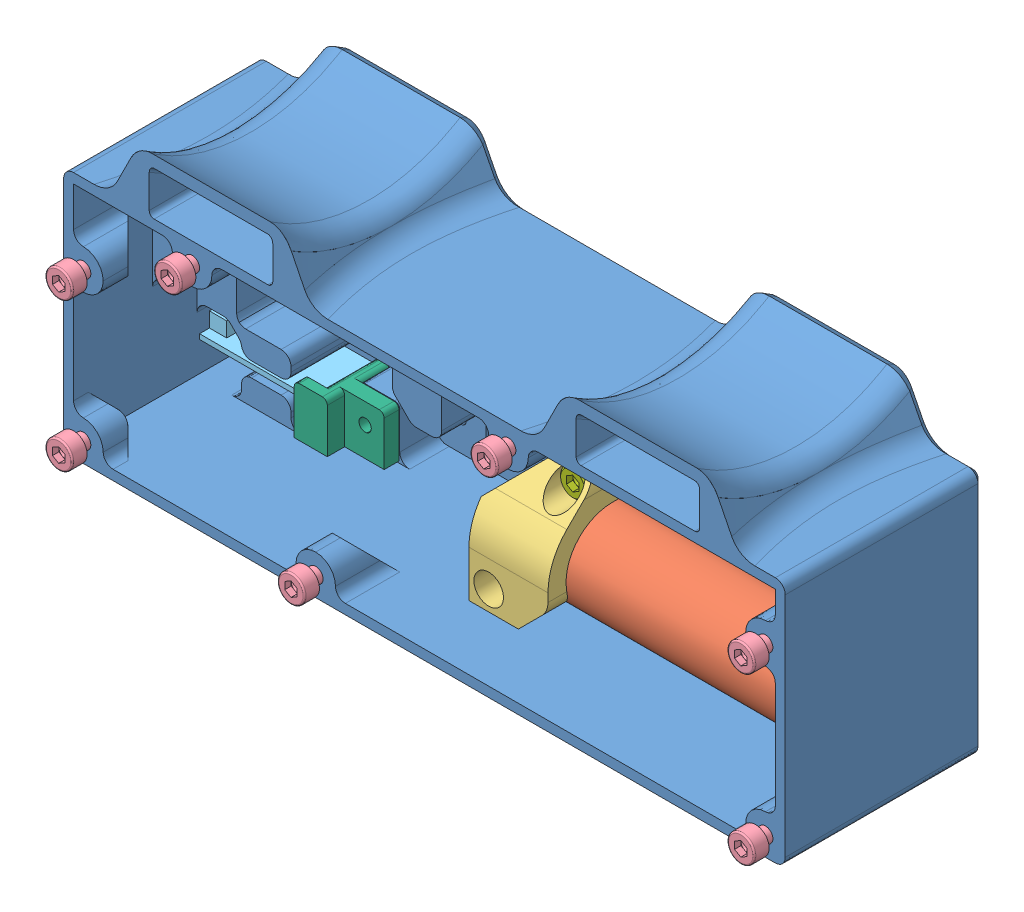
SolidWorks assembly TO-999, configuration Standard. Lengths in mm.
Overall size (146 61.68 45.85).
22 component instances, 8 part files, 75 mates.
Components (placement in the parent):
- TO-001-1: TO-001 [Standard] at origin size (146 61.68 40.85)
- socket head cap screw_am-1: socket head cap screw_am [B18.3.1M - 1.6 x 0.35 x 3 Hex SHCS -- 3NHX] at (97.7855 41.9451 16.2) x (0 0 -1) z (1 0 0) size (4.6 3 3) (hidden)
- socket head cap screw_am-2: socket head cap screw_am [B18.3.1M - 1.6 x 0.35 x 3 Hex SHCS -- 3NHX] at (138.85 24.8 16.2) x (0 0 -1) z (1 0 0) size (4.6 3 3) (hidden)
- socket head cap screw_am-4: socket head cap screw_am [B18.3.1M - 2.5 x 0.45 x 20 Hex SHCS -- 20NHX] at (48.5 42 28) x (0 0 -1) z (1 0 0) size (22.5 4.5 4.5) (hidden)
- socket head cap screw_am-5: socket head cap screw_am [B18.3.1M - 2.5 x 0.45 x 20 Hex SHCS -- 20NHX] at (48.5 17.5 28) x (0 0 -1) z (1 0 0) size (22.5 4.5 4.5) (hidden)
- socket head cap screw_am-6: socket head cap screw_am [B18.3.1M - 2.5 x 0.45 x 20 Hex SHCS -- 20NHX] at (2 17.5 28) x (0 0 -1) z (1 0 0) size (22.5 4.5 4.5) (hidden)
- socket head cap screw_am-7: socket head cap screw_am [B18.3.1M - 2.5 x 0.45 x 20 Hex SHCS -- 20NHX] at (2 42 28) x (0 0 -1) z (1 0 0) size (22.5 4.5 4.5) (hidden)
- Battery-1: Battery [Standard] at (75 9.35 15) x (0 0 -1) z (1 0 0) size (18 18 65)
- To-002-1: To-002 [Standard] at origin size (142 46 28)
- socket head cap screw 4762_din-1: socket head cap screw 4762_din [EN ISO 4762 M1.6 x 2.5 - 2.5N] at (97.7855 41.9451 16.2) x (0 0 -1) z (1 0 0) size (4.1 3 3)
- TO-003-1: TO-003 [Standard] at origin size (146 50 2) (hidden)
- socket head cap screw 4762_din-20: socket head cap screw 4762_din [EN ISO 4762 M3 x 8 - 8N] at (23 43 45) x (0 0 -1) z (1 0 0) size (11 5.5 5.5)
- socket head cap screw 4762_din-21: socket head cap screw 4762_din [EN ISO 4762 M3 x 8 - 8N] at (87 43 45) x (0 0 -1) z (1 0 0) size (11 5.5 5.5)
- socket head cap screw 4762_din-22: socket head cap screw 4762_din [EN ISO 4762 M3 x 8 - 8N] at (139 34.5 45) x (0 0 -1) z (1 0 0) size (11 5.5 5.5)
- socket head cap screw 4762_din-24: socket head cap screw 4762_din [EN ISO 4762 M3 x 8 - 8N] at (48 1 45) x (0 0 -1) z (1 0 0) size (11 5.5 5.5)
- socket head cap screw 4762_din-25: socket head cap screw 4762_din [EN ISO 4762 M3 x 8 - 8N] at (1 1 45) x (0 0 -1) z (1 0 0) size (11 5.5 5.5)
- socket head cap screw 4762_din-26: socket head cap screw 4762_din [EN ISO 4762 M3 x 8 - 8N] at (1 31 45) x (0 0 -1) z (1 0 0) size (11 5.5 5.5)
- socket head cap screw 4762_din-27: socket head cap screw 4762_din [EN ISO 4762 M3 x 8 - 8N] at (139 1 45) x (0 0 -1) z (1 0 0) size (11 5.5 5.5)
- TP5000_placeholder-1: TP5000_placeholder [Standard] at (-1 5 14.5) x (1 0 0) z (0 1 0) size (27 12.5 4)
- TO-004-1: TO-004 [Standard] at (26.85 -0.6295 10) x (1 0 0) z (0 1 0) size (14.7 12.5 10)
- socket head cap screw_am-8: socket head cap screw_am [B18.3.1M - 3 x 0.5 x 5 Hex SHCS -- 5NHX] at (79 22 19) x (0 0 -1) z (1 0 0) size (8 5.5 5.5)
- socket head cap screw_am-9: socket head cap screw_am [B18.3.1M - 3 x 0.5 x 5 Hex SHCS -- 5NHX] at (71 4 19) x (0 0 -1) z (1 0 0) size (8 5.5 5.5)
Mates (geometry in assembly coordinates):
- Konzentrisch1: concentric: cylinder of TO-001-1 through (138.85 24.8 13) axis (0 0 1) radius 0.9; cylinder of ? through (138.85 24.8 13) axis (0 0 1) radius 1
- Parallel1: parallel: plane of TO-001-1 through (141 45 40) normal (-1 0 0); plane of ? through (140.6177 22.9225 13) normal (1 0 0)
- Deckungsgleich2: coincident: plane of TO-001-1 through (130.3 33.55 13) normal (0 0 1); plane of ? through (140.6177 43.8225 13) normal (0 0 -1)
- Konzentrisch2: concentric: cylinder of TO-001-1 through (1 41.5 15) axis (0 0 1) radius 0.9; cylinder of ? through (2 42 25.5) axis (0 0 -1) radius 1.5
- Konzentrisch3: concentric: cylinder of TO-001-1 through (52.5 18 15) axis (0 0 1) radius 0.9; cylinder of ? through (48.5 17.5 25.5) axis (0 0 -1) radius 1.5
- Deckungsgleich4: coincident: plane of TO-001-1 through (0 0 24) normal (0 0 1); plane of ? through (25.25 29.75 24) normal (0 0 -1)
- Konzentrisch4: concentric: cylinder of ? through (97.7855 41.9451 13) axis (0 0 1) radius 1; cylinder of socket head cap screw_am-1 through (97.7855 41.9451 47.95) axis (0 0 1) radius 1.5
- Deckungsgleich5: coincident: plane of ? through (140.6177 43.8225 14.6) normal (0 0 1); plane of socket head cap screw_am-1 through (97.7855 43.4451 14.6) normal (0 0 -1)
- Konzentrisch5: concentric: cylinder of ? through (138.85 24.8 13) axis (0 0 1) radius 1; cylinder of socket head cap screw_am-2 through (138.85 24.8 47.95) axis (0 0 1) radius 1.5
- Deckungsgleich6: coincident: plane of ? through (140.6177 43.8225 14.6) normal (0 0 1); plane of socket head cap screw_am-2 through (138.85 26.3 14.6) normal (0 0 -1)
- Konzentrisch7: concentric: cylinder of ? through (48.5 42 25.5) axis (0 0 -1) radius 1.5; cylinder of socket head cap screw_am-4 through (48.5 42 59.75) axis (0 0 1) radius 2.25
- Deckungsgleich8: coincident: plane of ? through (25.25 29.75 25.5) normal (0 0 1); plane of socket head cap screw_am-4 through (48.5 44.25 25.5) normal (0 0 -1)
- Konzentrisch8: concentric: cylinder of ? through (48.5 17.5 25.5) axis (0 0 -1) radius 1.5; cylinder of socket head cap screw_am-5 through (48.5 17.5 59.75) axis (0 0 1) radius 2.25
- Deckungsgleich9: coincident: plane of ? through (25.25 29.75 25.5) normal (0 0 1); plane of socket head cap screw_am-5 through (48.5 19.75 25.5) normal (0 0 -1)
- Konzentrisch9: concentric: cylinder of ? through (2 17.5 25.5) axis (0 0 -1) radius 1.5; cylinder of socket head cap screw_am-6 through (2 17.5 59.75) axis (0 0 1) radius 2.25
- Deckungsgleich10: coincident: plane of ? through (25.25 29.75 25.5) normal (0 0 1); plane of socket head cap screw_am-6 through (2 19.75 25.5) normal (0 0 -1)
- Konzentrisch10: concentric: cylinder of ? through (2 42 25.5) axis (0 0 -1) radius 1.5; cylinder of socket head cap screw_am-7 through (2 42 59.75) axis (0 0 1) radius 2.25
- Deckungsgleich11: coincident: plane of ? through (25.25 29.75 25.5) normal (0 0 1); plane of socket head cap screw_am-7 through (2 44.25 25.5) normal (0 0 -1)
- Konzentrisch11: concentric: cylinder of TO-001-1 through (135 9.35 15) axis (1 0 0) radius 9.35; cylinder of Battery-1 through (140 9.35 15) axis (-1 0 0) radius 9
- Abstand1: distance = 1 mm: plane of Battery-1 through (140 9.35 15) normal (1 0 0); plane of TO-001-1 through (141 45 40) normal (-1 0 0)
- Konzentrisch12: concentric: cylinder of TO-001-1 through (79 22 8) axis (0 0 1) radius 1.25; cylinder of To-002-1 through (79 22 2) axis (0 0 -1) radius 1.5
- Konzentrisch13: concentric: cylinder of TO-001-1 through (71 4 8) axis (0 0 1) radius 1.25; cylinder of To-002-1 through (71 4 2) axis (0 0 -1) radius 1.5
- Konzentrisch14: concentric: cylinder of ? through (97.7855 41.9451 13) axis (0 0 1) radius 1; cylinder of socket head cap screw 4762_din-1 through (97.7855 41.9451 47.95) axis (0 0 1) radius 1.5
- Deckungsgleich13: coincident: plane of ? through (140.6177 43.8225 14.6) normal (0 0 1); plane of socket head cap screw 4762_din-1 through (97.7855 43.4451 14.6) normal (0 0 -1)
- Konzentrisch15: concentric: cylinder of ? through (138.85 24.8 13) axis (0 0 1) radius 1; cylinder of socket head cap screw_am-2 through (138.85 24.8 47.95) axis (0 0 1) radius 1.5
- Deckungsgleich14: coincident: plane of ? through (140.6177 43.8225 14.6) normal (0 0 1); plane of socket head cap screw_am-2 through (138.85 26.3 14.6) normal (0 0 -1)
- Konzentrisch16: concentric: cylinder of To-002-1 through (79 22 2) axis (0 0 -1) radius 1.5; cylinder of ? through (79 22 50.25) axis (0 0 1) radius 2.25
- Deckungsgleich15: coincident: plane of To-002-1 through (79 22 16) normal (0 0 1); plane of ? through (79 24.25 16) normal (0 0 -1)
- Konzentrisch17: concentric: cylinder of To-002-1 through (61 22 2) axis (0 0 -1) radius 1.5; cylinder of ? through (61 22 50.25) axis (0 0 1) radius 2.25
- Deckungsgleich16: coincident: plane of To-002-1 through (61 22 16) normal (0 0 1); plane of ? through (61 24.25 16) normal (0 0 -1)
- Konzentrisch18: concentric: cylinder of To-002-1 through (71 4 2) axis (0 0 -1) radius 1.5; cylinder of ? through (71 4 50.25) axis (0 0 1) radius 2.25
- Deckungsgleich17: coincident: plane of To-002-1 through (71 4 16) normal (0 0 1); plane of ? through (71 6.25 16) normal (0 0 -1)
- Konzentrisch19: concentric: cylinder of ? through (48.5 17.5 25.5) axis (0 0 -1) radius 1.5; cylinder of socket head cap screw_am-5 through (48.5 17.5 59.75) axis (0 0 1) radius 2.25
- Deckungsgleich18: coincident: plane of ? through (25.25 29.75 25.5) normal (0 0 1); plane of socket head cap screw_am-5 through (48.5 19.75 25.5) normal (0 0 -1)
- Konzentrisch20: concentric: cylinder of ? through (48.5 42 25.5) axis (0 0 -1) radius 1.5; cylinder of socket head cap screw_am-4 through (48.5 42 59.75) axis (0 0 1) radius 2.25
- Deckungsgleich19: coincident: plane of ? through (25.25 29.75 25.5) normal (0 0 1); plane of socket head cap screw_am-4 through (48.5 44.25 25.5) normal (0 0 -1)
- Konzentrisch21: concentric: cylinder of ? through (2 42 25.5) axis (0 0 -1) radius 1.5; cylinder of socket head cap screw_am-7 through (2 42 59.75) axis (0 0 1) radius 2.25
- Deckungsgleich20: coincident: plane of ? through (25.25 29.75 25.5) normal (0 0 1); plane of socket head cap screw_am-7 through (2 44.25 25.5) normal (0 0 -1)
- Konzentrisch22: concentric: cylinder of ? through (2 17.5 25.5) axis (0 0 -1) radius 1.5; cylinder of socket head cap screw_am-6 through (2 17.5 59.75) axis (0 0 1) radius 2.25
- Deckungsgleich21: coincident: plane of ? through (25.25 29.75 25.5) normal (0 0 1); plane of socket head cap screw_am-6 through (2 19.75 25.5) normal (0 0 -1)
- Konzentrisch23: concentric: cylinder of ? through (48.5 42 25.5) axis (0 0 -1) radius 1.5; cylinder of socket head cap screw_am-4 through (48.5 42 59.75) axis (0 0 1) radius 2.25
- Deckungsgleich22: coincident: plane of ? through (25.25 29.75 25.5) normal (0 0 1); plane of socket head cap screw_am-4 through (48.5 44.25 25.5) normal (0 0 -1)
- Konzentrisch24: concentric: cylinder of ? through (48.5 17.5 25.5) axis (0 0 -1) radius 1.5; cylinder of socket head cap screw_am-5 through (48.5 17.5 59.75) axis (0 0 1) radius 2.25
- Deckungsgleich23: coincident: plane of ? through (25.25 29.75 25.5) normal (0 0 1); plane of socket head cap screw_am-5 through (48.5 19.75 25.5) normal (0 0 -1)
- Konzentrisch25: concentric: cylinder of ? through (2 42 25.5) axis (0 0 -1) radius 1.5; cylinder of socket head cap screw_am-7 through (2 42 59.75) axis (0 0 1) radius 2.25
- Deckungsgleich24: coincident: plane of ? through (25.25 29.75 25.5) normal (0 0 1); plane of socket head cap screw_am-7 through (2 44.25 25.5) normal (0 0 -1)
- Konzentrisch26: concentric: cylinder of ? through (2 17.5 25.5) axis (0 0 -1) radius 1.5; cylinder of socket head cap screw_am-6 through (2 17.5 59.75) axis (0 0 1) radius 2.25
- Deckungsgleich25: coincident: plane of ? through (25.25 29.75 25.5) normal (0 0 1); plane of socket head cap screw_am-6 through (2 19.75 25.5) normal (0 0 -1)
- Deckungsgleich26: coincident: plane of TO-001-1 through (-158 63.1337 40) normal (0 0 1); plane of TO-003-1 through (0 0 40) normal (0 0 -1)
- Konzentrisch27: concentric: cylinder of TO-001-1 through (23 43 40) axis (0 0 1) radius 1.25; cylinder of TO-003-1 through (23 43 42) axis (0 0 1) radius 1.25
- Konzentrisch28: concentric: cylinder of TO-001-1 through (139 1 40) axis (0 0 1) radius 1.25; cylinder of TO-003-1 through (139 1 42) axis (0 0 1) radius 1.25
- Konzentrisch35: concentric: cylinder of TO-003-1 through (23 43 42) axis (0 0 1) radius 1.25; cylinder of socket head cap screw 4762_din-20 through (23 43 76.75) axis (0 0 1) radius 2.75
- Deckungsgleich33: coincident: plane of TO-003-1 through (0 0 42) normal (0 0 1); plane of socket head cap screw 4762_din-20 through (23 45.75 42) normal (0 0 -1)
- Konzentrisch36: concentric: cylinder of TO-003-1 through (87 43 42) axis (0 0 1) radius 1.25; cylinder of socket head cap screw 4762_din-21 through (87 43 76.75) axis (0 0 1) radius 2.75
- Deckungsgleich34: coincident: plane of TO-003-1 through (0 0 42) normal (0 0 1); plane of socket head cap screw 4762_din-21 through (87 45.75 42) normal (0 0 -1)
- Konzentrisch37: concentric: cylinder of TO-003-1 through (139 34.5 42) axis (0 0 1) radius 1.25; cylinder of socket head cap screw 4762_din-22 through (139 34.5 76.75) axis (0 0 1) radius 2.75
- Deckungsgleich35: coincident: plane of TO-003-1 through (0 0 42) normal (0 0 1); plane of socket head cap screw 4762_din-22 through (139 37.25 42) normal (0 0 -1)
- Konzentrisch38: concentric: cylinder of TO-003-1 through (48 1 42) axis (0 0 1) radius 1.25; cylinder of socket head cap screw 4762_din-24 through (48 1 76.75) axis (0 0 1) radius 2.75
- Deckungsgleich36: coincident: plane of TO-003-1 through (0 0 42) normal (0 0 1); plane of socket head cap screw 4762_din-24 through (48 3.75 42) normal (0 0 -1)
- Konzentrisch39: concentric: cylinder of TO-003-1 through (1 1 42) axis (0 0 1) radius 1.25; cylinder of socket head cap screw 4762_din-25 through (1 1 76.75) axis (0 0 1) radius 2.75
- Deckungsgleich37: coincident: plane of TO-003-1 through (0 0 42) normal (0 0 1); plane of socket head cap screw 4762_din-25 through (1 3.75 42) normal (0 0 -1)
- Konzentrisch40: concentric: cylinder of TO-003-1 through (1 31 42) axis (0 0 1) radius 1.25; cylinder of socket head cap screw 4762_din-26 through (1 31 76.75) axis (0 0 1) radius 2.75
- Deckungsgleich38: coincident: plane of TO-003-1 through (0 0 42) normal (0 0 1); plane of socket head cap screw 4762_din-26 through (1 33.75 42) normal (0 0 -1)
- Konzentrisch41: concentric: cylinder of TO-003-1 through (139 1 42) axis (0 0 1) radius 1.25; cylinder of socket head cap screw 4762_din-27 through (139 1 76.75) axis (0 0 1) radius 2.75
- Deckungsgleich39: coincident: plane of TO-003-1 through (0 0 42) normal (0 0 1); plane of socket head cap screw 4762_din-27 through (139 3.75 42) normal (0 0 -1)
- Deckungsgleich40: coincident: plane of TO-001-1 through (-14.5 9 4) normal (0 -1 0); plane of TP5000_placeholder-1 through (-1 9 14.5) normal (0 1 0)
- Deckungsgleich41: coincident: plane of TO-001-1 through (-1 45 40) normal (1 0 0); plane of TP5000_placeholder-1 through (-1 6 14.5) normal (-1 0 0)
- Deckungsgleich42: coincident: plane of TO-001-1 through (0 0 2) normal (0 0 1); plane of TP5000_placeholder-1 through (-1 6 2) normal (0 0 -1)
- Konzentrisch42: concentric: cylinder of TO-001-1 through (31 5.25 10) axis (0 0 1) radius 1.25; cylinder of TO-004-1 through (31 5.25 13) axis (0 0 1) radius 1.25
- Deckungsgleich44: coincident: plane of TO-001-1 through (0 0 10) normal (0 0 1); plane of TO-004-1 through (26.85 9.3705 10) normal (0 0 -1)
- Parallel2: parallel: plane of TO-001-1 through (27 9.5 10) normal (-1 0 0); plane of TO-004-1 through (34.85 9.3705 10) normal (1 0 0)
- Konzentrisch43: concentric: cylinder of To-002-1 through (79 22 2) axis (0 0 -1) radius 1.5; cylinder of socket head cap screw_am-8 through (79 22 50.75) axis (0 0 1) radius 2.75
- Deckungsgleich45: coincident: plane of To-002-1 through (79 22 16) normal (0 0 1); plane of socket head cap screw_am-8 through (79 24.75 16) normal (0 0 -1)
- Konzentrisch44: concentric: cylinder of To-002-1 through (71 4 2) axis (0 0 -1) radius 1.5; cylinder of socket head cap screw_am-9 through (71 4 50.75) axis (0 0 1) radius 2.75
- Deckungsgleich46: coincident: plane of To-002-1 through (71 4 16) normal (0 0 1); plane of socket head cap screw_am-9 through (71 6.75 16) normal (0 0 -1)
